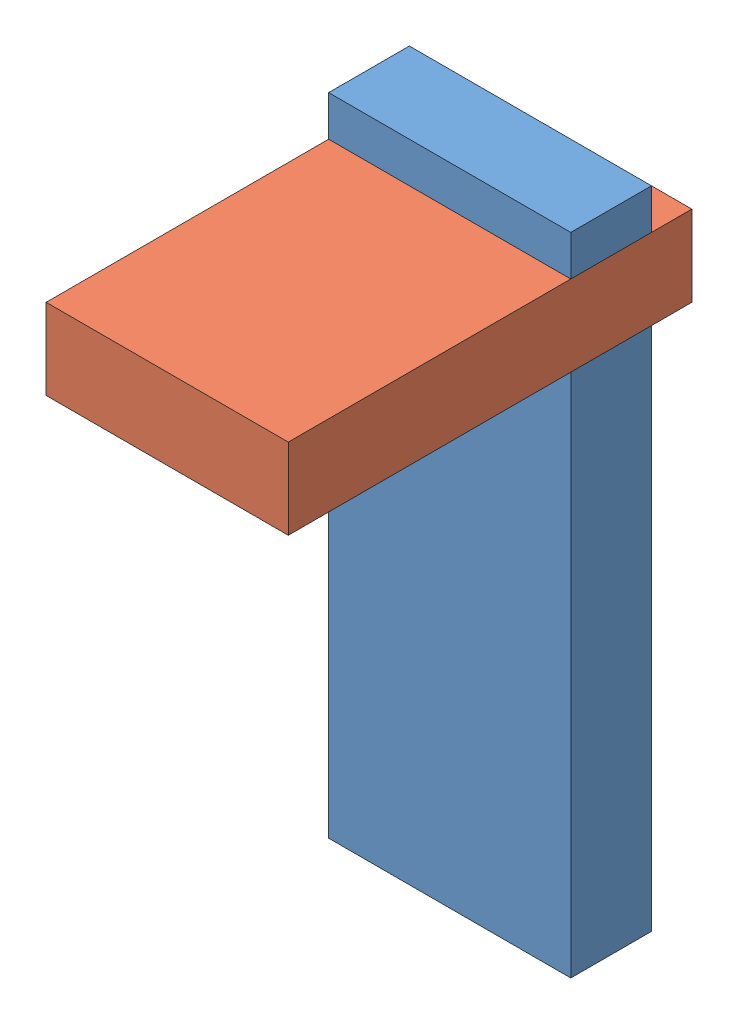
SolidWorks assembly Assem2, configuration Default. Lengths in mm.
Overall size (38.1 101.6 63.5).
2 component instances, 2 part files, 3 mates.
Components (placement in the parent):
- handle1-1: handle1 [Default] at (-23.8616 -27.2799 31.125) size (38.1 101.6 12.7)
- handle2-1: handle2 [Default] at (-23.8616 67.9701 24.775) x (1 0 0) z (0 -1 0) size (38.1 63.5 12.7)
Mates (geometry in assembly coordinates):
- Coincident7: coincident anti-aligned: plane of handle1-1 through (-4.8116 55.2701 43.825) normal (0 1 0); plane of handle2-1 through (-23.8616 55.2701 43.825) normal (0 -1 0)
- Coincident8: coincident anti-aligned: plane of handle1-1 through (-4.8116 67.9701 43.825) normal (1 0 0); plane of handle2-1 through (-4.8116 55.2701 43.825) normal (-1 0 0)
- Coincident10: coincident aligned: line of handle1-1; line of handle2-1
